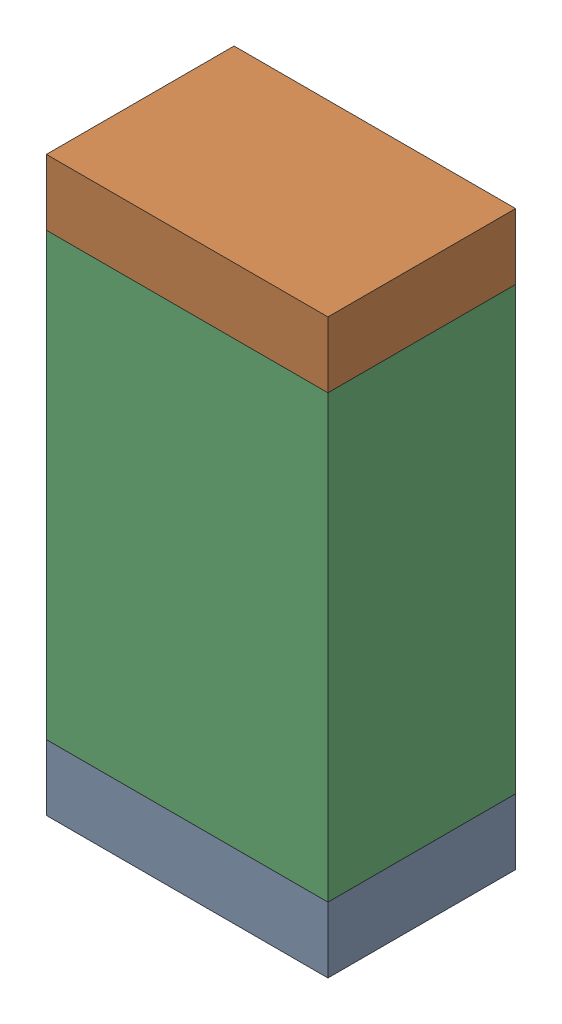
SolidWorks assembly C8, configuration Default. Lengths in mm.
Overall size (0.76 1.55 0.51).
6 component instances, 2 part files, 0 mates.
Components (placement in the parent):
- 822501776-1: 822501776 [Default] at (32.876 2.0467 0) size (0.76 0.18 0.51)
  - Extruded_3-1: Extruded_3 [Default] at origin size (0.76 0.18 0.51)
- 822501776-2: 822501776 [Default] at (32.876 3.4183 0) size (0.76 0.18 0.51)
  - Extruded_3-1: Extruded_3 [Default] at origin size (0.76 0.18 0.51)
- 822501912-1: 822501912 [Default] at (32.876 2.7325 0) size (0.76 1.19 0.51)
  - Extruded_4-1: Extruded_4 [Default] at origin size (0.76 1.19 0.51)
